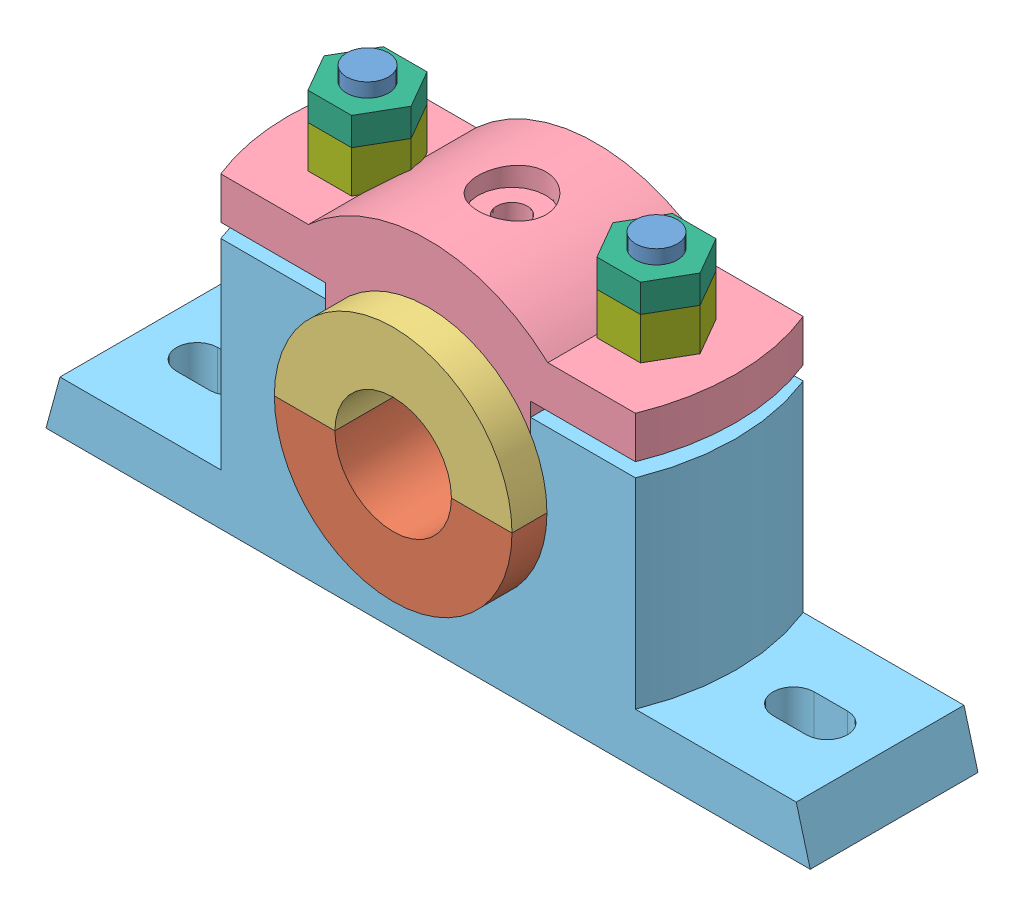
SolidWorks assembly Assem1, configuration Default. Lengths in mm.
Overall size (164 84 51).
10 component instances, 7 part files, 12 mates.
Components (placement in the parent):
- bolt-1: bolt [Default] at (146.8649 47.9883 -29.79) size (19 82 19)
- brass-1: brass [Default] at (115.8649 83.9883 -4.29) x (1 0 0) z (0 1 0) size (51 51 25.5)
- brasses-1: brasses [Default] at (115.8649 83.9883 -4.29) x (0 0 -1) z (0 1 0) size (51 51 25.5)
- CAP-1: CAP [Default] at (115.8649 83.9883 -29.79) size (96 32 36)
- Casting-1: Casting [Default] at (115.8649 45.9883 -29.79) size (164 54 36)
- locknut-1: locknut [Default] at (146.8649 126.9883 -29.79) x (1 0 0) z (0 -1 0) size (18.71 16.2 6)
- Nuts-1: Nuts [Default] at (146.8649 111.9883 -29.79) size (18.71 9 16.2)
- bolt-2: bolt [Default] at (84.8649 47.9883 -29.79) x (-1 0 0) z (0 0 -1) size (19 82 19)
- locknut-2: locknut [Default] at (84.8649 120.9883 -29.79) x (-1 0 0) z (0 1 0) size (18.71 16.2 6)
- Nuts-2: Nuts [Default] at (84.8649 111.9883 -29.79) x (-1 0 0) z (0 0 -1) size (18.71 9 16.2)
Mates (geometry in assembly coordinates):
- Concentric1: concentric anti-aligned: cylinder of brass-1 through (115.8649 83.9893 -29.79) axis (0 -1 0) radius 3; cylinder of Casting-1 through (115.8649 64.9883 -29.79) axis (0 1 0) radius 3
- Concentric2: concentric anti-aligned: cylinder of brass-1 through (115.8649 83.9883 -4.29) axis (0 0 1) radius 17.5; cylinder of Casting-1 through (115.8649 83.9883 -11.79) axis (0 0 -1) radius 19
- Concentric3: concentric anti-aligned: cylinder of brass-1 through (115.8649 83.9883 -4.29) axis (0 0 -1) radius 12.5; cylinder of brasses-1 through (115.8649 83.9883 -55.29) axis (0 0 1) radius 12.5
- Coincident1: coincident aligned: plane of brass-1 through (115.8649 83.9883 -4.29) normal (0 0 1); plane of brasses-1 through (115.8649 83.9883 -4.29) normal (0 0 1)
- Concentric4: concentric anti-aligned: cylinder of brasses-1 through (115.8649 83.9883 -4.29) axis (0 0 1) radius 17.5; cylinder of CAP-1 through (115.8649 83.9883 -11.79) axis (0 0 -1) radius 19
- Coincident2: coincident aligned: plane of CAP-1 through (115.8649 83.9883 -11.79) normal (0 0 1); plane of Casting-1 through (115.8649 83.9883 -11.79) normal (0 0 1)
- Concentric5: concentric anti-aligned: cylinder of bolt-1 through (146.8649 129.9883 -29.79) axis (0 -1 0) radius 4.5; cylinder of Casting-1 through (146.8649 99.9883 -29.79) axis (0 1 0) radius 4
- Coincident3: coincident anti-aligned: plane of bolt-1 through (146.8649 53.9883 -29.79) normal (0 1 0); plane of Casting-1 through (115.8649 53.9883 -29.79) normal (0 -1 0)
- Concentric6: concentric aligned: cylinder of bolt-1 through (146.8649 129.9883 -29.79) axis (0 -1 0) radius 4.5; cylinder of Nuts-1 through (146.8649 120.9883 -29.79) axis (0 -1 0) radius 4.5
- Coincident4: coincident anti-aligned: plane of CAP-1 through (145.2458 111.9883 -11.79) normal (0 1 0); plane of Nuts-1 through (146.8649 111.9883 -29.79) normal (0 -1 0)
- Concentric7: concentric anti-aligned: cylinder of bolt-1 through (146.8649 129.9883 -29.79) axis (0 -1 0) radius 4.5; cylinder of locknut-1 through (146.8649 120.9883 -29.79) axis (0 1 0) radius 4.5
- Coincident5: coincident anti-aligned: plane of locknut-1 through (146.8649 120.9883 -29.79) normal (0 -1 0); plane of Nuts-1 through (146.8649 120.9883 -29.79) normal (0 1 0)
